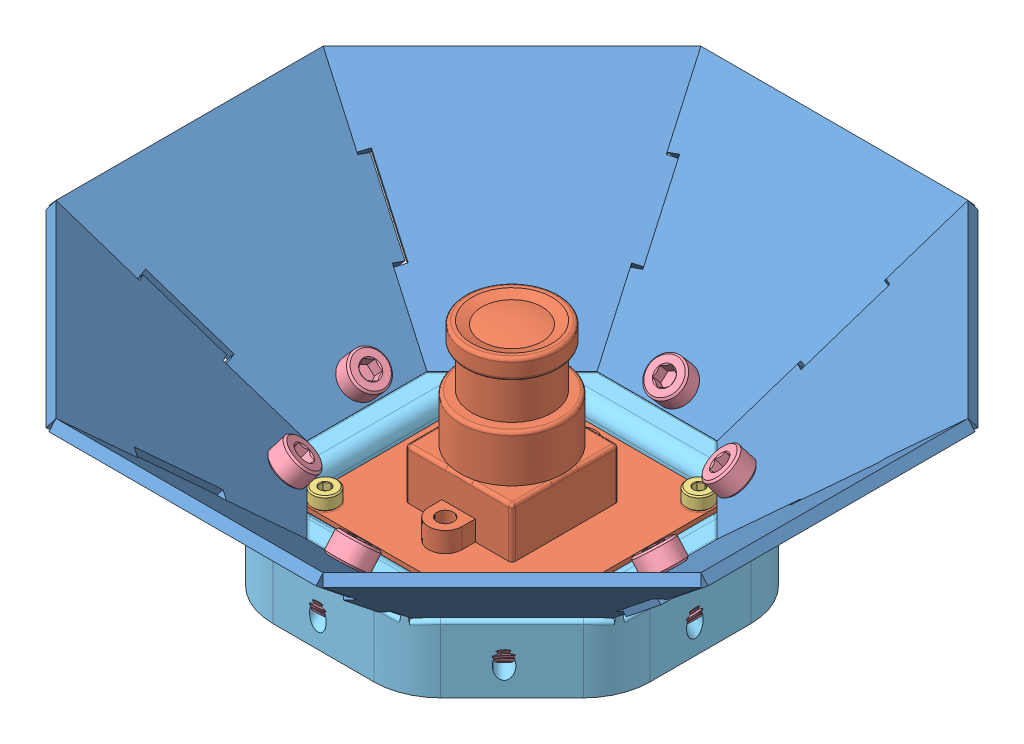
SolidWorks assembly LED Ring Assembly, configuration Default. Lengths in mm.
Overall size (98.69 32.42 98.69).
22 component instances, 5 part files, 35 mates.
Components (placement in the parent):
- Bottom LED Board Shape-1: Bottom LED Board Shape [Default] at (0 -1.0999 0) size (27.61 24.62 40)
- Bottom LED Board Shape-2: Bottom LED Board Shape [Default] at (-1.1847 -1.0999 -0.4907) x (0.707107 0 0.707107) z (-0.707107 0 0.707107) size (27.61 24.62 40)
- Bottom LED Board Shape-3: Bottom LED Board Shape [Default] at (1.1847 -1.0999 -0.4907) x (0.707107 0 -0.707107) z (0.707107 0 0.707107) size (27.61 24.62 40)
- Bottom LED Board Shape-4: Bottom LED Board Shape [Default] at (-1.6754 -1.0999 -1.6754) x (0 0 1) z (-1 0 0) size (27.61 24.62 40)
- Bottom LED Board Shape-5: Bottom LED Board Shape [Default] at (-1.1847 -1.0999 -2.8601) x (-0.707107 0 0.707107) z (-0.707107 0 -0.707107) size (27.61 24.62 40)
- Bottom LED Board Shape-6: Bottom LED Board Shape [Default] at (1.6754 -1.0999 -1.6754) x (0 0 -1) z (1 0 0) size (27.61 24.62 40)
- Bottom LED Board Shape-7: Bottom LED Board Shape [Default] at (1.1847 -1.0999 -2.8601) x (-0.707107 0 -0.707107) z (0.707107 0 -0.707107) size (27.61 24.62 40)
- Bottom LED Board Shape-8: Bottom LED Board Shape [Default] at (0 -1.0999 -3.3508) x (-1 0 0) z (0 0 -1) size (27.61 24.62 40)
- 32mm Board Camera-1: 32mm Board Camera [Default] at (0 -4.0999 -1.6754) x (0 0 1) z (0 1 0) size (32 32 31)
- Bolt M2x6mm Socket Head-1: Bolt M2x6mm Socket Head [90128A178] at (-14 -8.5999 12.3246) x (1 0 0) z (0 -1 0) size (3.8 3.8 8.1)
- Bolt M3x6mm Socket Head-1: Bolt M3x6mm Socket Head [95263A110] at (-0.8377 -3.6153 26.2713) x (1 0 0) z (0 -0.749964 0.661479) size (5.5 5.5 9.19)
- Bolt M2x6mm Socket Head-2: Bolt M2x6mm Socket Head [90128A178] at (-14 -8.5999 -15.6754) x (1 0 0) z (0 -1 0) size (3.8 3.8 8.1)
- Bolt M2x6mm Socket Head-3: Bolt M2x6mm Socket Head [90128A178] at (14 -8.5999 -15.6754) x (1 0 0) z (0 -1 0) size (3.8 3.8 8.1)
- Bolt M2x6mm Socket Head-4: Bolt M2x6mm Socket Head [90128A178] at (14 -8.5999 12.3246) x (1 0 0) z (0 -1 0) size (3.8 3.8 8.1)
- Bolt M3x6mm Socket Head-2: Bolt M3x6mm Socket Head [95263A110] at (-20.3536 -3.6153 17.4935) x (0.707107 0 0.707107) z (-0.467736 -0.749964 0.467736) size (5.5 5.5 9.19)
- Bolt M3x6mm Socket Head-3: Bolt M3x6mm Socket Head [95263A110] at (-27.9467 -3.6153 -2.5131) x (0 0 1) z (-0.661479 -0.749964 0) size (5.5 5.5 9.19)
- Bolt M3x6mm Socket Head-4: Bolt M3x6mm Socket Head [95263A110] at (-19.1689 -3.6153 -22.0291) x (-0.707107 0 0.707107) z (-0.467736 -0.749964 -0.467736) size (5.5 5.5 9.19)
- Bolt M3x6mm Socket Head-5: Bolt M3x6mm Socket Head [95263A110] at (0.8377 -3.6153 -29.6221) x (-1 0 0) z (0 -0.749964 -0.661479) size (5.5 5.5 9.19)
- Bolt M3x6mm Socket Head-6: Bolt M3x6mm Socket Head [95263A110] at (20.3536 -3.6153 -20.8444) x (-0.707107 0 -0.707107) z (0.467736 -0.749964 -0.467736) size (5.5 5.5 9.19)
- Bolt M3x6mm Socket Head-7: Bolt M3x6mm Socket Head [95263A110] at (27.9467 -3.6153 -0.8377) x (0 0 -1) z (0.661479 -0.749964 0) size (5.5 5.5 9.19)
- Bolt M3x6mm Socket Head-8: Bolt M3x6mm Socket Head [95263A110] at (19.1689 -3.6153 18.6782) x (0.707107 0 -0.707107) z (0.467736 -0.749964 0.467736) size (5.5 5.5 9.19)
- Bottom Camera Mount-1: Bottom Camera Mount [Default] at (0 -8.0999 -1.6754) size (56.46 11.8 56.46)
Mates (geometry in assembly coordinates):
- Coincident1: coincident: point of Bottom LED Board Shape-1; point of Bottom LED Board Shape-2
- Coincident2: coincident: point of Bottom LED Board Shape-1; point of Bottom LED Board Shape-2
- Coincident3: coincident: point of Bottom LED Board Shape-1; point of Bottom LED Board Shape-3
- Coincident4: coincident: point of Bottom LED Board Shape-1; point of Bottom LED Board Shape-3
- Coincident5: coincident: point of Bottom LED Board Shape-2; point of Bottom LED Board Shape-4
- Coincident6: coincident: point of Bottom LED Board Shape-2; point of Bottom LED Board Shape-4
- Coincident7: coincident: point of Bottom LED Board Shape-4; point of Bottom LED Board Shape-5
- Coincident8: coincident: point of Bottom LED Board Shape-4; point of Bottom LED Board Shape-5
- Coincident9: coincident: point of Bottom LED Board Shape-3; point of Bottom LED Board Shape-6
- Coincident10: coincident: point of Bottom LED Board Shape-3; point of Bottom LED Board Shape-6
- Coincident11: coincident: point of Bottom LED Board Shape-6; point of Bottom LED Board Shape-7
- Coincident12: coincident: point of Bottom LED Board Shape-6; point of Bottom LED Board Shape-7
- Coincident13: coincident: point of Bottom LED Board Shape-7; point of Bottom LED Board Shape-8
- Coincident14: coincident: point of Bottom LED Board Shape-7; point of Bottom LED Board Shape-8
- Coincident15: coincident: point of Bottom LED Board Shape-5; point of Bottom LED Board Shape-8
- Parallel1: parallel anti-aligned: line of Bottom LED Board Shape-3 through (21.7279 -1.0999 -10.6754) axis (-0.707107 0 -0.707107); line of Bottom LED Board Shape-5 through (-21.7279 -1.0999 7.3246) axis (0.707107 0 0.707107)
- Parallel2: parallel anti-aligned: line of Bottom LED Board Shape-2 through (9 -1.0999 20.0525) axis (0.707107 0 -0.707107); line of Bottom LED Board Shape-7 through (-9 -1.0999 -23.4033) axis (-0.707107 0 0.707107)
- Parallel3: parallel anti-aligned: line of Bottom LED Board Shape-4 through (-9 -1.0999 20.0525) axis (1 0 0); line of Bottom LED Board Shape-6 through (9 -1.0999 -23.4033) axis (-1 0 0)
- Concentric1: concentric anti-aligned: cylinder of 32mm Board Camera-1 through (-14 -4.0999 12.3246) axis (0 1 0) radius 1.25; cylinder of Bolt M2x6mm Socket Head-1 through (-14 -0.5999 12.3246) axis (0 -1 0) radius 1.9
- Coincident22: coincident anti-aligned: plane of 32mm Board Camera-1 through (0 -2.5999 -1.6754) normal (0 1 0); plane of Bolt M2x6mm Socket Head-1 through (-14 -2.5999 12.3246) normal (0 -1 0)
- Concentric2: concentric anti-aligned: cylinder of 32mm Board Camera-1 through (14 -4.0999 12.3246) axis (0 1 0) radius 1.25; cylinder of Bolt M2x6mm Socket Head-4 through (14 -0.5999 12.3246) axis (0 -1 0) radius 1.9
- Concentric3: concentric anti-aligned: cylinder of 32mm Board Camera-1 through (14 -4.0999 -15.6754) axis (0 1 0) radius 1.25; cylinder of Bolt M2x6mm Socket Head-3 through (14 -0.5999 -15.6754) axis (0 -1 0) radius 1.9
- Concentric4: concentric anti-aligned: cylinder of 32mm Board Camera-1 through (-14 -4.0999 -15.6754) axis (0 1 0) radius 1.25; cylinder of Bolt M2x6mm Socket Head-2 through (-14 -0.5999 -15.6754) axis (0 -1 0) radius 1.9
- Coincident23: coincident aligned: plane of Bolt M2x6mm Socket Head-1 through (-14 -0.5999 12.3246) normal (0 1 0); plane of Bolt M2x6mm Socket Head-2 through (-14 -0.5999 -15.6754) normal (0 1 0)
- Coincident24: coincident aligned: plane of Bolt M2x6mm Socket Head-1 through (-14 -0.5999 12.3246) normal (0 1 0); plane of Bolt M2x6mm Socket Head-4 through (14 -0.5999 12.3246) normal (0 1 0)
- Coincident25: coincident aligned: plane of Bolt M2x6mm Socket Head-2 through (-14 -0.5999 -15.6754) normal (0 1 0); plane of Bolt M2x6mm Socket Head-3 through (14 -0.5999 -15.6754) normal (0 1 0)
- Concentric5: concentric anti-aligned: cylinder of Bottom LED Board Shape-4 through (-0.8377 0.8845 22.3024) axis (0 0.749964 -0.661479) radius 1.7; cylinder of Bolt M3x6mm Socket Head-1 through (-0.8377 3.1344 20.318) axis (0 -0.749964 0.661479) radius 2.75
- Coincident26: coincident anti-aligned: plane of Bottom LED Board Shape-4 through (-1.6754 -11.8788 7.8317) normal (0 0.749964 -0.661479); plane of Bolt M3x6mm Socket Head-1 through (-0.8377 0.8845 22.3024) normal (0 -0.749964 0.661479)
- Coincident28: coincident anti-aligned: plane of 32mm Board Camera-1; plane of assembly through (0 0 0) normal (-1 0 0)
- Coincident29: coincident anti-aligned: plane of 32mm Board Camera-1; plane of assembly through (0 0 -1.6754) normal (0 0 -1)
- Concentric6: concentric anti-aligned: cylinder of Bolt M2x6mm Socket Head-1 through (-14 -0.5999 12.3246) axis (0 -1 0) radius 1.9; cylinder of Bottom Camera Mount-1 through (-14 -1.0999 12.3246) axis (0 1 0) radius 0.8
- Concentric7: concentric anti-aligned: cylinder of Bolt M2x6mm Socket Head-3 through (14 -0.5999 -15.6754) axis (0 -1 0) radius 1.9; cylinder of Bottom Camera Mount-1 through (14 -1.0999 -15.6754) axis (0 1 0) radius 0.8
- Coincident30: coincident anti-aligned: plane of 32mm Board Camera-1 through (0 -4.0999 -1.6754) normal (0 -1 0); plane of Bottom Camera Mount-1 through (0 -4.0999 -1.6754) normal (0 1 0)
- Coincident31: coincident anti-aligned: plane of Bottom LED Board Shape-1 through (10.5655 -13.0788 0) normal (0.661479 -0.749964 0); plane of Bottom Camera Mount-1 through (7.0929 -16.1417 -1.6754) normal (-0.661479 0.749964 0)
- Coincident32: coincident anti-aligned: plane of Bottom LED Board Shape-8 through (-10.5655 -13.0788 -3.3508) normal (-0.661479 -0.749964 0); plane of Bottom Camera Mount-1 through (-7.0929 -16.1417 -1.6754) normal (0.661479 0.749964 0)
